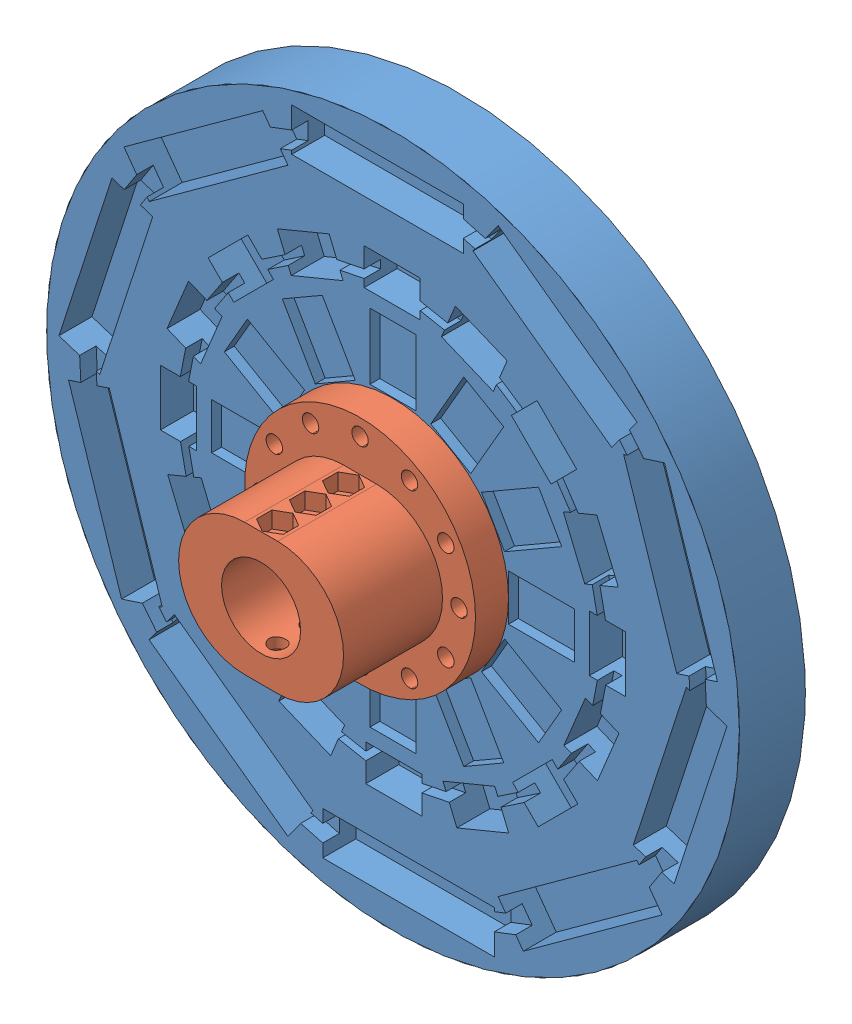
SolidWorks assembly Assembly, configuration Default. Lengths in mm.
Overall size (210 210 60.3).
2 component instances, 2 part files, 0 mates.
Components (placement in the parent):
- FerriteAndLoad-2: FerriteAndLoad [Default] at (46.0165 -49.6637 190.9008) size (210 210 20)
- coupling-2: coupling [Default] at (46.3254 -49.5725 221.2003) size (70 70 40)
